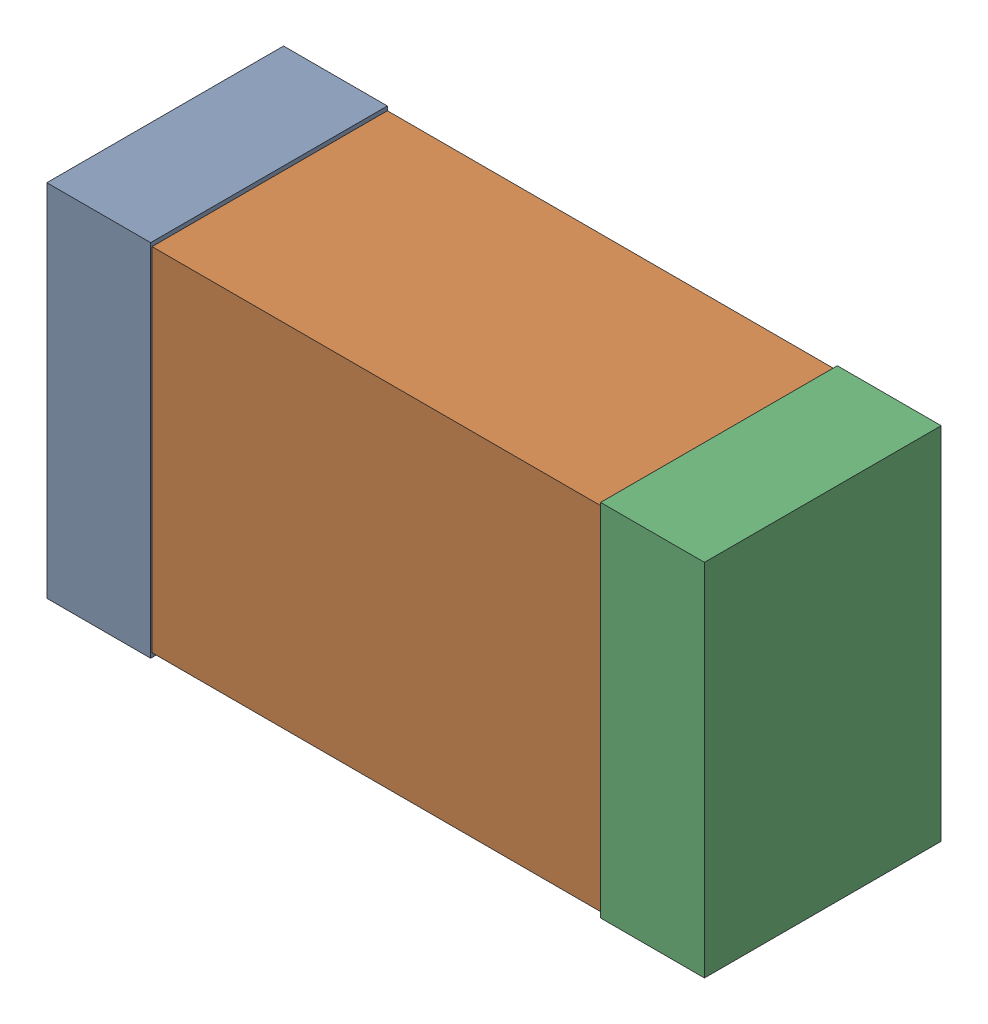
SolidWorks assembly 4.7uFKanaloa_v2.0.0_Power, configuration Default. Lengths in mm.
Overall size (2.38 1.3 0.85).
6 component instances, 2 part files, 0 mates.
Components (placement in the parent):
- 352877648-1: 352877648 [Default] at (142.6508 93.3684 0) size (0.38 1.3 0.85)
  - Extruded_14-1: Extruded_14 [Default] at origin size (0.38 1.3 0.85)
- 352877392-1: 352877392 [Default] at (143.6508 93.3684 0) size (2.2 1.27 0.85)
  - Extruded_15-1: Extruded_15 [Default] at origin size (2.2 1.27 0.85)
- 352877648-2: 352877648 [Default] at (144.6508 93.3684 0) size (0.38 1.3 0.85)
  - Extruded_14-1: Extruded_14 [Default] at origin size (0.38 1.3 0.85)
